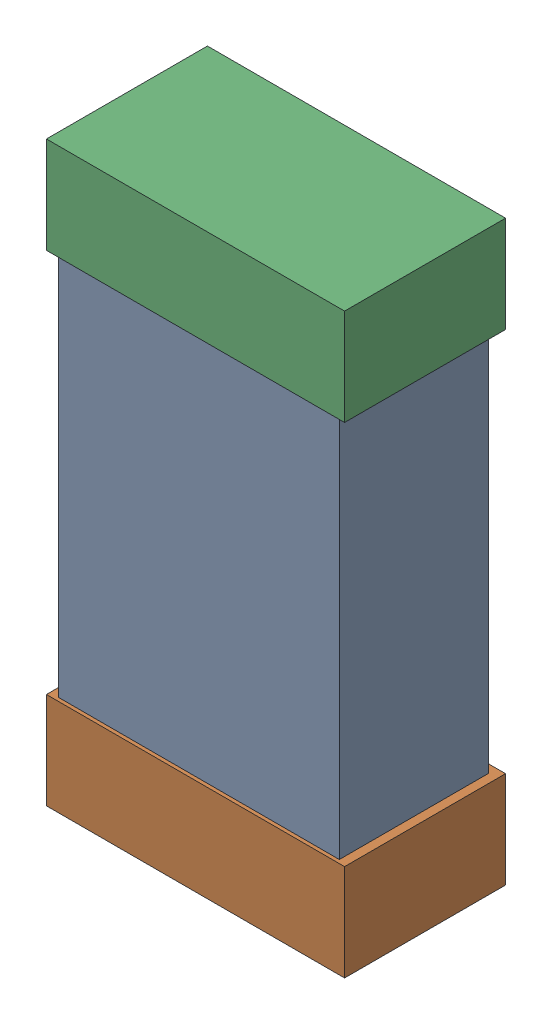
SolidWorks assembly C16, configuration Default. Lengths in mm.
Overall size (0.85 1.65 0.46).
6 component instances, 2 part files, 0 mates.
Components (placement in the parent):
- 432124816_32-1: 432124816_32 [Default] at (32.6957 22.0613 0.025) size (0.8 1.5 0.42)
  - Extruded (1)-1: Extruded (1) [Default] at origin size (0.8 1.5 0.42)
- 432138512_64-1: 432138512_64 [Default] at (32.6957 21.3755 0.001) size (0.85 0.28 0.46)
  - Extruded-1: Extruded [Default] at origin size (0.85 0.28 0.46)
- 432138512_65-1: 432138512_65 [Default] at (32.6957 22.7471 0.001) size (0.85 0.28 0.46)
  - Extruded-1: Extruded [Default] at origin size (0.85 0.28 0.46)
